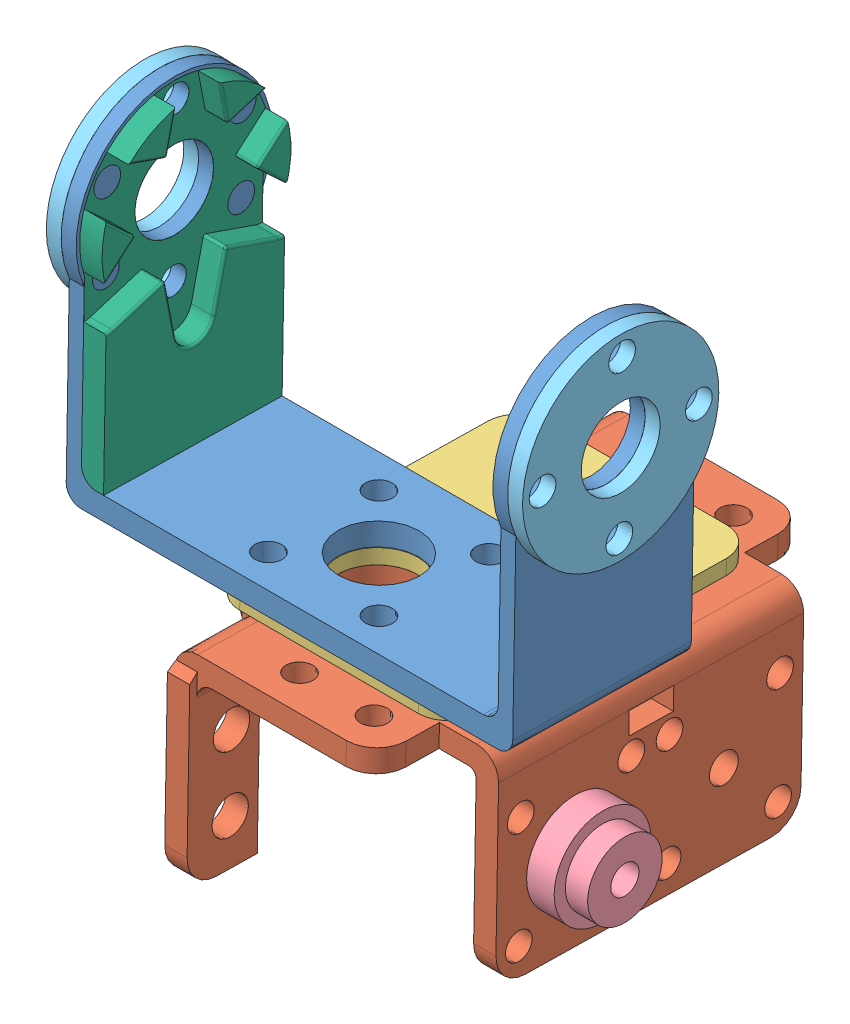
SolidWorks assembly box2_right_bushing, configuration Predeterminado. Lengths in mm.
Overall size (65.67 74.14 60.47).
8 component instances, 6 part files, 11 mates.
Components (placement in the parent):
- box2_right-1: box2_right [Predeterminado] at (2.9022 60.2896 -29.0999) size (60 74.14 60.47)
  - u_bracket-1: u_bracket [Predeterminado] at (-18.6428 -64.1261 18.1896) x (1 0 0) z (0 0.017646 0.999844) size (60 44.22 26.36)
  - multi_purpose_bracket-3: multi_purpose_bracket [Predeterminado] at (-6.4228 -67.2977 8.4941) x (0 -0.017646 -0.999844) z (-1 0 0) size (60 27 38.5)
  - box1_supplement-1: box1_supplement [Predeterminado] at (-14.1428 -67.2944 8.679) x (1 0 0) z (0 0.017646 0.999844) size (32 2 41.37)
- bushing-1: bushing [Predeterminado] at (13.7294 -22.6991 -10.3274) x (0 -1 0) z (0 0 1) size (13 6.7 13)
- suplement_external_bracket-1: suplement_external_bracket [Predeterminado] at (-47.7406 26.1989 -11.4404) x (0 0.017646 0.999844) z (0 0.999844 -0.017646) size (26.36 2 26.36)
- supplement_u_f_horn-1: supplement_u_f_horn [Predeterminado] at (-43.7406 26.1989 -11.4404) x (0 0.999844 -0.017646) z (0 -0.017646 -0.999844) size (40.74 3.02 25.4)
- suplement_external_bracket-2: suplement_external_bracket [Predeterminado] at (14.2594 26.1989 -11.4404) x (0 -0.999844 0.017646) z (0 0.017646 0.999844) size (26.36 2 26.36)
Mates (geometry in assembly coordinates):
- Coincidente6: coincident anti-aligned: plane of box2_right-1/multi_purpose_bracket-3 through (11.2294 -34.3656 -40.6262) normal (1 0 0); plane of bushing-1 through (11.2294 -22.6991 -10.3274) normal (-1 0 0)
- Concéntrica1: concentric anti-aligned: cylinder of box2_right-1/multi_purpose_bracket-3 through (-27.2716 -22.6991 -10.3274) axis (1 0 0) radius 1.95; cylinder of bushing-1 through (17.9304 -22.6991 -10.3274) axis (-1 0 0) radius 1.9
- Coincidente7: coincident anti-aligned: plane of box2_right-1/u_bracket-1 through (-45.7406 -2.0485 -22.9438) normal (-1 0 0); plane of suplement_external_bracket-1 through (-45.7406 26.1989 -11.4404) normal (1 0 0)
- Concéntrica2: concentric aligned: cylinder of box2_right-1/u_bracket-1 through (-43.7406 26.1989 -11.4404) axis (-1 0 0) radius 5.3; cylinder of suplement_external_bracket-1 through (-45.7406 26.1989 -11.4404) axis (-1 0 0) radius 5.3
- Concéntrica3: concentric anti-aligned: cylinder of box2_right-1/u_bracket-1 through (14.2604 26.3842 -0.9421) axis (-1 0 0) radius 1.8; cylinder of suplement_external_bracket-1 through (-47.7406 26.3842 -0.9421) axis (1 0 0) radius 1.8
- Coincidente10: coincident anti-aligned: cylinder of box2_right-1/u_bracket-1 through (-43.7406 26.1989 -11.4404) axis (-1 0 0) radius 5.3; circle of supplement_u_f_horn-1
- Paralelo1: parallel aligned: plane of box2_right-1/u_bracket-1 through (-45.7406 -1.625 1.0525) normal (0 0.017646 0.999844); plane of supplement_u_f_horn-1 through (-40.7406 -1.625 1.0525) normal (0 0.017646 0.999844)
- Coincidente12: coincident anti-aligned: plane of box2_right-1/u_bracket-1 through (-43.7406 26.1989 -11.4404) normal (1 0 0); plane of supplement_u_f_horn-1 through (-43.7406 26.1989 -11.4404) normal (-1 0 0)
- Concéntrica4: concentric: cylinder of box2_right-1/u_bracket-1 through (12.2594 26.1989 -11.4404) axis (1 0 0) radius 5.3; cylinder of suplement_external_bracket-2 through (16.2594 26.1989 -11.4404) axis (-1 0 0) radius 5.3
- Coincidente13: coincident: plane of box2_right-1/u_bracket-1 through (14.2594 -2.0485 -22.9438) normal (1 0 0); plane of suplement_external_bracket-2 through (14.2594 26.1989 -11.4404) normal (-1 0 0)
- Concéntrica5: concentric aligned: cylinder of box2_right-1/u_bracket-1 through (-45.7416 26.3842 -0.9421) axis (1 0 0) radius 1.8; cylinder of suplement_external_bracket-2 through (14.2594 26.3842 -0.9421) axis (1 0 0) radius 1.8
